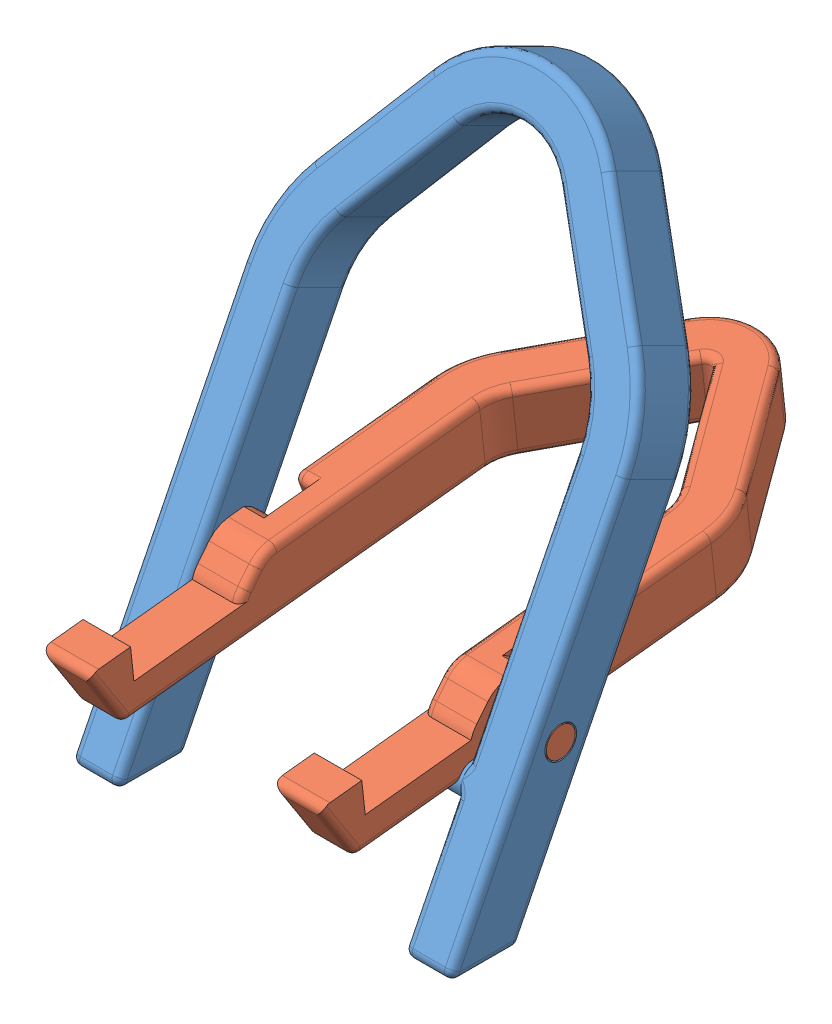
SolidWorks assembly Assem1, configuration Default. Lengths in mm.
Overall size (76.2 118.49 116.44).
2 component instances, 2 part files, 5 mates.
Components (placement in the parent):
- Outer-1: Outer [Default] at (0 -5.6796 -10.2564) x (1 0 0) z (0 0.447214 0.894427) size (76.2 126.13 12.7)
- Inner-1: Inner [Default] at (0 20.801 15.5731) x (1 0 0) z (0 0.994124 0.108246) size (76.2 115.75 12.7)
Mates (geometry in assembly coordinates):
- Coincident1: coincident: plane of Outer-1 through (0 -5.6796 -10.2564) normal (1 0 0); plane of assembly through (0 0 0) normal (1 0 0)
- Coincident2: coincident: plane of Outer-1 through (-38.1 0 1.1028) normal (0 -1 0); plane of assembly through (0 0 0) normal (0 1 0)
- Coincident3: coincident: line of Outer-1 through (-36.576 2.2056 0) axis (1 0 0); plane of assembly
- Concentric1: concentric: cylinder of Outer-1 through (-38.1 31.2379 -21.6157) axis (1 0 0) radius 3.175; cylinder of Inner-1 through (-38.1 31.2379 -21.6157) axis (1 0 0) radius 2.921
- Width1: width: plane of Outer-1 through (-28.575 64.8811 -45.5368) normal (1 0 0); plane of Outer-1 through (28.575 -5.6796 -10.2564) normal (-1 0 0); plane of Inner-1 through (27.94 41.9945 -61.7411) normal (1 0 0); plane of Inner-1 through (-27.94 41.9945 -61.7411) normal (-1 0 0)
